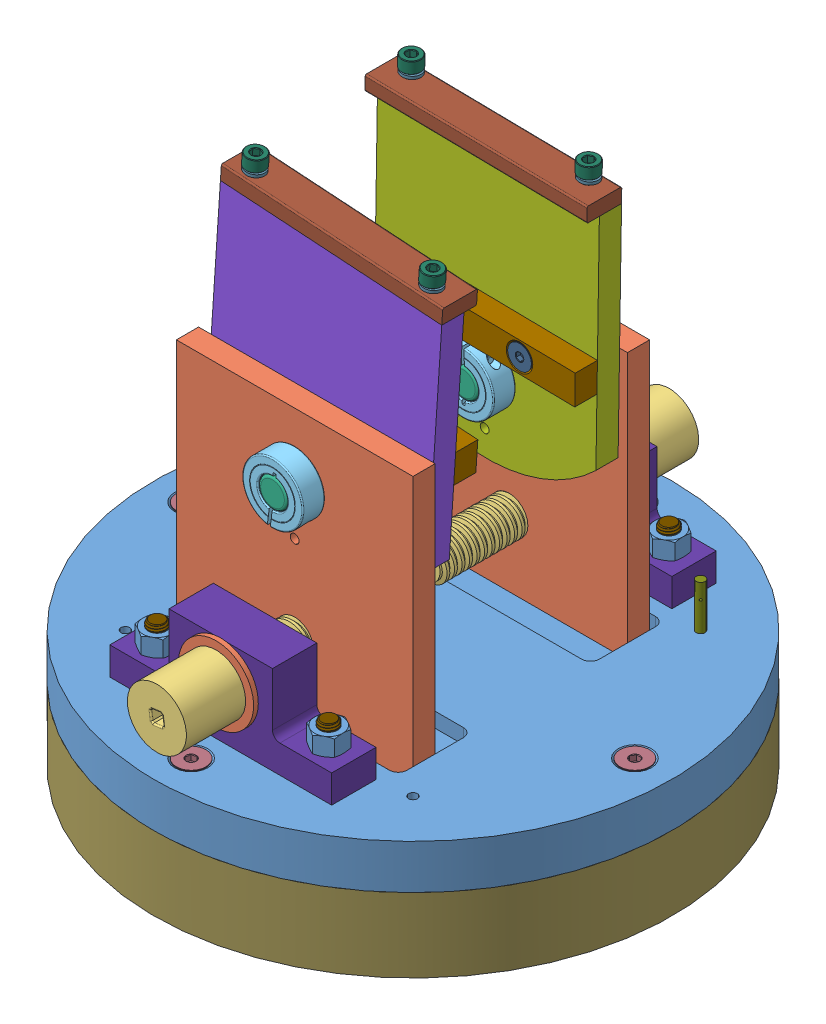
SolidWorks assembly Satalite mount assembly, configuration Default. Lengths in mm.
Overall size (350 354.15 350).
53 component instances, 21 part files, 116 mates.
Components (placement in the parent):
- satalite mount bottom plate-1: satalite mount bottom plate [Default] at (141.1689 151.6595 277.362) size (350 30 350)
- Satalite mount outside plate-1: Satalite mount outside plate [Default] at (141.1689 266.6595 342.352) size (160 180 15)
- Satalite mount outside plate-2: Satalite mount outside plate [Default] at (141.1689 266.6595 197.372) size (160 180 15)
- 20mm shaft buffer-1: 20mm shaft buffer [Default] at (141.1689 309.1595 342.352) x (1 0 0) z (0 1 0) size (25 1 25)
- rotory shaft outer plastic bearing-1: rotory shaft outer plastic bearing [Default] at (141.1689 309.1595 342.352) size (26 26 15)
- rotory shaft outer plastic bearing-2: rotory shaft outer plastic bearing [Default] at (141.1689 309.1595 342.352) x (0.815735 -0.578426 0) z (0 0 1) size (26 26 15)
- rotory shaft outer plastic bearing-3: rotory shaft outer plastic bearing [Default] at (141.1689 309.1595 197.372) size (26 26 15)
- rotory shaft outer plastic bearing-4: rotory shaft outer plastic bearing [Default] at (141.1689 309.1595 197.372) size (26 26 15)
- 20mm shaft collar-1: 20mm shaft collar [57445K73] at (141.1689 309.1595 318.852) x (-0.923728 -0.383049 0) z (0 0 -1) size (41 41.02 15.09)
- 20mm shaft collar-2: 20mm shaft collar [57445K73] at (141.1689 309.1595 364.852) x (-0.992379 0.123223 0) z (0 0 1) size (41 41.02 15.09)
- 20mm shaft collar-3: 20mm shaft collar [57445K73] at (141.1689 309.1595 235.872) x (0.999679 0.025332 0) z (0 0 1) size (41 41.02 15.09)
- 20mm shaft collar-4: 20mm shaft collar [57445K73] at (141.1689 309.1595 189.872) x (0.923728 0.383049 0) z (0 0 -1) size (41 41.02 15.09)
- 20mm shaft-1: 20mm shaft [Default] at (141.1689 309.1595 182.372) x (0.421421 -0.906865 0) z (-0.906865 -0.421421 0) size (20 61 20)
- 20mm shaft-2: 20mm shaft [Default] at (141.1689 309.1595 311.352) x (0.923728 0.383049 0) z (0.383049 -0.923728 0) size (20 61 20)
- 20mm shaft buffer-2: 20mm shaft buffer [Default] at (141.1689 309.1595 212.372) x (1 0 0) z (0 -1 0) size (25 1 25)
- satalite rightside inside mount-4: satalite rightside inside mount [Default] at (142.4964 394.1491 213.372) x (0.999878 -0.015617 0) z (0 0 1) size (150 181.07 15)
- satalite left mount-2: satalite left mount [Default] at (146.7984 393.9729 326.352) x (0.997804 -0.066229 0) z (0 0 1) size (150 181.07 15)
- satalite mount side rest-1: satalite mount side rest [Default] at (141.7155 344.1552 243.372) x (-0.999878 0.015617 0) z (0 0 -1) size (150 20 15)
- M8 22mm ctrsk screw-1: M8 22mm ctrsk screw [91294A285] at (104.2201 344.7409 243.372) size (16 16 22.74)
- M8 22mm ctrsk screw-2: M8 22mm ctrsk screw [91294A285] at (179.211 343.5696 243.372) size (16 16 22.74)
- satalite mount side rest-2: satalite mount side rest [Default] at (143.487 344.0827 311.352) x (0.997804 -0.066229 0) z (0 0 1) size (150 20 15)
- M8 22mm ctrsk screw-3: M8 22mm ctrsk screw [91294A285] at (180.9046 341.5991 311.352) x (0.640146 0.768253 0) z (0 0 -1) size (16 16 22.74)
- M8 22mm ctrsk screw-4: M8 22mm ctrsk screw [91294A285] at (106.0693 346.5663 310.952) x (-0.483512 -0.875338 0) z (0 0 -1) size (16 16 22.74)
- satalite mount adjustable clamp-1: satalite mount adjustable clamp [Default] at (68.2864 445.3144 225.122) x (0 0 -1) z (-0.015617 -0.999878 0) size (23.5 150 10)
- satalite mount adjustable clamp-2: satalite mount adjustable clamp [Default] at (224.9452 438.8959 329.602) x (0 0 1) z (-0.066229 -0.997804 0) size (23.5 150 10)
- Rotary table top plate-1: Rotary table top plate [Default] at (141.1689 121.6595 277.362) x (0.707107 0 0.707107) z (-0.707107 0 0.707107) size (350 50 350) (hidden)
- M10 hex 35mm-1: M10 hex 35mm [91304A165] at (141.1689 181.6595 427.362) x (-0.306479 0 -0.951877) z (0 1 0) size (20 20 35.94)
- M10 hex 35mm-2: M10 hex 35mm [91304A165] at (291.1689 181.6595 277.362) x (-0.884177 0 -0.467152) z (0 1 0) size (20 20 35.94)
- M10 hex 35mm-3: M10 hex 35mm [91304A165] at (-8.8311 181.6595 277.362) x (1 0 0) z (0 1 0) size (20 20 35.94)
- M10 hex 35mm-4: M10 hex 35mm [91304A165] at (141.1689 181.6595 127.362) x (1 0 0) z (0 1 0) size (20 20 35.94)
- M8 spring washer-1: M8 spring washer [91190A550] at (90.7238 455.1009 333.852) x (0.995294 -0.066063 -0.070888) z (0.070732 -0.004695 0.997484) size (12.81 4.18 14.61)
- M8 spring washer-2: M8 spring washer [91190A550] at (83.3983 452.3592 220.872) x (0.999878 -0.015617 0.000121) z (-0.00012 0.000002 1) size (12.81 4.18 14.61)
- M8 spring washer-3: M8 spring washer [91190A550] at (210.4603 447.1534 333.852) x (0.995294 -0.066063 -0.070888) z (0.070732 -0.004695 0.997484) size (12.81 4.18 14.61)
- M8 spring washer-4: M8 spring washer [91190A550] at (203.3837 450.4851 220.872) x (0.999878 -0.015617 0) z (0 0 1) size (12.81 4.18 14.61)
- M8 Hex fastener 45mm L-1: M8 Hex fastener 45mm L [91290A446] at (87.8693 412.0955 333.852) x (0.986596 -0.065486 -0.149465) z (-0.066229 -0.997804 0) size (13 13 53.81)
- M8 Hex fastener 45mm L-2: M8 Hex fastener 45mm L [91290A446] at (82.7252 409.2645 220.872) x (0.997959 -0.015587 0.061925) z (-0.015617 -0.999878 0) size (13 13 53.81)
- M8 Hex fastener 45mm L-3: M8 Hex fastener 45mm L [91290A446] at (207.6058 404.148 333.852) x (0.986596 -0.065486 -0.149465) z (-0.066229 -0.997804 0) size (13 13 53.81)
- M8 Hex fastener 45mm L-4: M8 Hex fastener 45mm L [91290A446] at (202.7106 407.3904 220.872) x (0.997959 -0.015587 0.061925) z (-0.015617 -0.999878 0) size (13 13 53.81)
- quick release pin-1: quick release pin [Default] at (238.3961 111.6595 180.1348) size (5.98 100 15.53)
- mount vice mount-1: mount vice mount [Default] at (141.1689 205.1118 147.362) size (150 60 30)
- mount vice mount-2: mount vice mount [Default] at (141.1689 205.1118 377.362) size (150 60 30)
- M12_65L_hex-1: M12_65L_hex [91294A556] at (83.1689 151.6595 392.362) x (1 0 0) z (0 -1 0) size (24 24 66.3)
- M12_65L_hex-2: M12_65L_hex [91294A556] at (199.1689 151.6595 392.362) x (1 0 0) z (0 -1 0) size (24 24 66.3)
- M12_65L_hex-3: M12_65L_hex [91294A556] at (199.1689 151.6595 162.362) x (1 0 0) z (0 -1 0) size (24 24 66.3)
- M12_65L_hex-4: M12_65L_hex [91294A556] at (83.1689 151.6595 162.362) x (1 0 0) z (0 -1 0) size (24 24 66.3)
- M12 Nut-1: M12 Nut [90725A725] at (199.1689 206.5419 162.362) size (19 13.08 21.94)
- M12 Nut-2: M12 Nut [90725A725] at (83.1689 206.5419 162.362) size (19 13.08 21.94)
- M12 Nut-3: M12 Nut [90725A725] at (199.1689 206.5419 392.362) size (19 13.08 21.94)
- M12 Nut-4: M12 Nut [90725A725] at (83.1689 206.5419 392.362) size (19 13.08 21.94)
- Vise bushing-1: Vise bushing [Default] at (141.1689 216.6595 410.537) x (1 0 0) z (0 1 0) size (50.8 3.17 50.8)
- Vise_shaft-1: Vise_shaft [Default] at (141.1689 216.6595 410.537) x (0.991544 0.129771 0) z (-0.129771 0.991544 0) size (40 165 40)
- Vise_shaft-2: Vise_shaft [Default] at (141.1689 216.6595 144.187) x (1 0 0) z (0 -1 0) size (40 165 40)
- Vise bushing-2: Vise bushing [Default] at (141.1689 216.6595 144.187) x (1 0 0) z (0 -1 0) size (50.8 3.17 50.8)
Mates (geometry in assembly coordinates):
- Coincident3: coincident aligned: plane of Satalite mount outside plate-1 through (141.1689 266.6595 357.352) normal (0 0 1); plane of rotory shaft outer plastic bearing-1 through (141.1689 309.1595 357.352) normal (0 0 1)
- Concentric2: concentric anti-aligned: cylinder of Satalite mount outside plate-1 through (141.1689 309.1595 357.352) axis (0 0 1) radius 13.005; cylinder of rotory shaft outer plastic bearing-1 through (141.1689 309.1595 357.352) axis (0 0 -1) radius 10
- Concentric5: concentric anti-aligned: cylinder of Satalite mount outside plate-2 through (141.1689 309.1595 212.372) axis (0 0 1) radius 13.005; cylinder of rotory shaft outer plastic bearing-3 through (141.1689 309.1595 212.372) axis (0 0 -1) radius 10
- Concentric6: concentric anti-aligned: cylinder of Satalite mount outside plate-2 through (141.1689 309.1595 212.372) axis (0 0 1) radius 13.005; cylinder of rotory shaft outer plastic bearing-3 through (141.1689 309.1595 212.372) axis (0 0 -1) radius 10
- Coincident6: coincident aligned: plane of Satalite mount outside plate-2 through (141.1689 266.6595 212.372) normal (0 0 1); plane of rotory shaft outer plastic bearing-3 through (141.1689 309.1595 212.372) normal (0 0 1)
- Concentric7: concentric anti-aligned: cylinder of 20mm shaft buffer-1 through (141.1689 309.1595 341.352) axis (0 0 1) radius 10.05; cylinder of rotory shaft outer plastic bearing-2 through (141.1689 309.1595 357.352) axis (0 0 -1) radius 10
- Coincident8: coincident anti-aligned: plane of Satalite mount outside plate-1 through (141.1689 266.6595 342.352) normal (0 0 -1); plane of 20mm shaft buffer-1 through (141.1689 309.1595 342.352) normal (0 0 1)
- Coincident10: coincident anti-aligned: plane of Satalite mount outside plate-1 through (141.1689 266.6595 357.352) normal (0 0 1); plane of 20mm shaft collar-2 through (141.1689 309.1595 357.352) normal (0 0 -1)
- Concentric8: concentric aligned: cylinder of rotory shaft outer plastic bearing-1 through (141.1689 309.1595 357.352) axis (0 0 -1) radius 10; cylinder of 20mm shaft collar-2 through (141.1689 309.1595 372.352) axis (0 0 -1) radius 10
- Coincident11: coincident aligned: plane of 20mm shaft collar-2 through (141.1689 309.1595 372.352) normal (0 0 1); plane of 20mm shaft-2 through (141.1689 309.1595 372.352) normal (0 0 1)
- Concentric9: concentric aligned: cylinder of 20mm shaft collar-2 through (141.1689 309.1595 372.352) axis (0 0 -1) radius 10; cylinder of 20mm shaft-2 through (141.1689 309.1595 372.352) axis (0 0 -1) radius 10
- Concentric10: concentric anti-aligned: cylinder of 20mm shaft collar-1 through (141.1689 309.1595 311.352) axis (0 0 1) radius 10; cylinder of 20mm shaft-2 through (141.1689 309.1595 372.352) axis (0 0 -1) radius 10
- Concentric11: concentric aligned: cylinder of rotory shaft outer plastic bearing-4 through (141.1689 309.1595 212.372) axis (0 0 -1) radius 10; cylinder of 20mm shaft buffer-2 through (141.1689 309.1595 213.372) axis (0 0 -1) radius 10.05
- Coincident16: coincident anti-aligned: plane of Satalite mount outside plate-2 through (141.1689 266.6595 212.372) normal (0 0 1); plane of 20mm shaft buffer-2 through (141.1689 309.1595 212.372) normal (0 0 -1)
- Concentric12: concentric aligned: cylinder of rotory shaft outer plastic bearing-3 through (141.1689 309.1595 212.372) axis (0 0 -1) radius 10; cylinder of rotory shaft outer plastic bearing-4 through (141.1689 309.1595 212.372) axis (0 0 -1) radius 10
- Coincident18: coincident anti-aligned: plane of Satalite mount outside plate-2 through (141.1689 266.6595 197.372) normal (0 0 -1); plane of 20mm shaft collar-4 through (141.1689 309.1595 197.372) normal (0 0 1)
- Coincident19: coincident aligned: plane of 20mm shaft collar-4 through (141.1689 309.1595 182.372) normal (0 0 -1); plane of 20mm shaft-1 through (141.1689 309.1595 182.372) normal (0 0 -1)
- Concentric15: concentric anti-aligned: cylinder of 20mm shaft collar-4 through (141.1689 309.1595 182.372) axis (0 0 1) radius 10; cylinder of 20mm shaft-1 through (141.1689 309.1595 243.372) axis (0 0 -1) radius 10
- Concentric16: concentric aligned: cylinder of 20mm shaft collar-3 through (141.1689 309.1595 243.372) axis (0 0 -1) radius 10; cylinder of 20mm shaft-1 through (141.1689 309.1595 243.372) axis (0 0 -1) radius 10
- Concentric17: concentric anti-aligned: cylinder of rotory shaft outer plastic bearing-2 through (141.1689 309.1595 357.352) axis (0 0 -1) radius 13; cylinder of satalite left mount-2 through (141.1689 309.1595 326.352) axis (0 0 1) radius 13.005
- Coincident21: coincident anti-aligned: circle of 20mm shaft collar-1; plane of satalite left mount-2 through (146.7984 393.9729 326.352) normal (0 0 -1)
- Coincident22: coincident aligned: plane of 20mm shaft collar-1 through (141.1689 309.1595 311.352) normal (0 0 -1); plane of 20mm shaft-2 through (141.1689 309.1595 311.352) normal (0 0 -1)
- Concentric18: concentric aligned: cylinder of rotory shaft outer plastic bearing-2 through (141.1689 309.1595 357.352) axis (0 0 -1) radius 10; cylinder of 20mm shaft-2 through (141.1689 309.1595 372.352) axis (0 0 -1) radius 10
- Concentric19: concentric aligned: circle of 20mm shaft-1; cylinder of satalite rightside inside mount-4 through (141.1689 309.1595 213.372) axis (0 0 1) radius 13.005
- Coincident24: coincident anti-aligned: plane of 20mm shaft collar-3 through (141.1689 309.1595 228.372) normal (0 0 -1); plane of satalite rightside inside mount-4 through (142.4964 394.1491 228.372) normal (0 0 1)
- Concentric20: concentric aligned: cylinder of rotory shaft outer plastic bearing-4 through (141.1689 309.1595 212.372) axis (0 0 -1) radius 10; cylinder of 20mm shaft-1 through (141.1689 309.1595 243.372) axis (0 0 -1) radius 10
- Coincident25: coincident aligned: plane of 20mm shaft collar-3 through (141.1689 309.1595 243.372) normal (0 0 1); plane of 20mm shaft-1 through (141.1689 309.1595 243.372) normal (0 0 1)
- Coincident26: coincident anti-aligned: plane of satalite rightside inside mount-4 through (142.4964 394.1491 228.372) normal (0 0 1); plane of satalite mount side rest-1 through (141.7155 344.1552 228.372) normal (0 0 -1)
- Parallel2: parallel aligned: plane of satalite rightside inside mount-4 through (217.4873 392.9778 228.372) normal (0.999878 -0.015617 0); plane of satalite mount side rest-1 through (216.5502 332.9852 228.372) normal (0.999878 -0.015617 0)
- Concentric21: concentric aligned: cylinder of satalite rightside inside mount-4 through (179.211 343.5696 228.372) axis (0 0 1) radius 3.4; cylinder of satalite mount side rest-1 through (179.211 343.5696 243.372) axis (0 0 1) radius 4.5
- Coincident29: coincident aligned: plane of satalite mount side rest-1 through (141.7155 344.1552 243.372) normal (0 0 1); plane of M8 22mm ctrsk screw-1 through (104.2201 340.7409 243.372) normal (0 0 1)
- Concentric22: concentric aligned: cylinder of satalite mount side rest-1 through (104.2201 344.7409 243.372) axis (0 0 1) radius 4.5; circle of M8 22mm ctrsk screw-1
- Coincident30: coincident aligned: plane of satalite mount side rest-1 through (141.7155 344.1552 243.372) normal (0 0 1); plane of M8 22mm ctrsk screw-2 through (179.211 339.5696 243.372) normal (0 0 1)
- Concentric23: concentric aligned: cylinder of satalite mount side rest-1 through (179.211 343.5696 243.372) axis (0 0 1) radius 4.5; circle of M8 22mm ctrsk screw-2
- Coincident31: coincident anti-aligned: plane of satalite left mount-2 through (146.7984 393.9729 326.352) normal (0 0 -1); plane of satalite mount side rest-2 through (143.487 344.0827 326.352) normal (0 0 1)
- Parallel3: parallel aligned: plane of satalite left mount-2 through (221.6338 389.0057 341.352) normal (0.997804 -0.066229 0); plane of satalite mount side rest-2 through (217.66 329.1374 326.352) normal (0.997804 -0.066229 0)
- Concentric24: concentric aligned: cylinder of satalite left mount-2 through (180.9046 341.5991 326.352) axis (0 0 -1) radius 3.4; cylinder of satalite mount side rest-2 through (180.9046 341.5991 311.352) axis (0 0 -1) radius 4.5
- Concentric25: concentric aligned: cylinder of satalite mount side rest-2 through (180.9046 341.5991 311.352) axis (0 0 -1) radius 4.5; cylinder of M8 22mm ctrsk screw-3 through (180.9046 341.5991 311.352) axis (0 0 -1) radius 8
- Coincident33: coincident aligned: plane of satalite mount side rest-2 through (143.487 344.0827 311.352) normal (0 0 -1); plane of M8 22mm ctrsk screw-3 through (177.8316 344.1596 311.352) normal (0 0 -1)
- Coincident34: coincident aligned: plane of satalite mount side rest-2 through (143.487 344.0827 311.352) normal (0 0 -1); circle of M8 22mm ctrsk screw-4
- Concentric26: concentric aligned: cylinder of satalite mount side rest-2 through (106.0693 346.5663 311.352) axis (0 0 -1) radius 4.5; cylinder of M8 22mm ctrsk screw-4 through (106.0693 346.5663 310.952) axis (0 0 -1) radius 8
- Coincident35: coincident anti-aligned: plane of satalite left mount-2 through (149.7788 438.8741 341.352) normal (0.066229 0.997804 0); plane of satalite mount adjustable clamp-2 through (74.9434 443.8413 318.852) normal (-0.066229 -0.997804 0)
- Concentric27: concentric aligned: cylinder of satalite left mount-2 through (89.9105 442.8479 333.852) axis (0.066229 0.997804 0) radius 3.4; cylinder of satalite mount adjustable clamp-2 through (90.5728 452.8259 333.852) axis (0.066229 0.997804 0) radius 4.5
- Concentric28: concentric aligned: cylinder of satalite left mount-2 through (209.647 434.9003 333.852) axis (0.066229 0.997804 0) radius 3.4; cylinder of satalite mount adjustable clamp-2 through (210.3093 444.8784 333.852) axis (0.066229 0.997804 0) radius 4.5
- Coincident38: coincident anti-aligned: plane of satalite rightside inside mount-4 through (143.1992 439.1437 228.372) normal (0.015617 0.999878 0); plane of satalite mount adjustable clamp-1 through (218.1901 437.9724 235.872) normal (-0.015617 -0.999878 0)
- Concentric29: concentric aligned: cylinder of satalite rightside inside mount-4 through (203.1919 438.2066 220.872) axis (0.015617 0.999878 0) radius 3.4; cylinder of satalite mount adjustable clamp-1 through (203.3481 448.2054 220.872) axis (0.015617 0.999878 0) radius 4.5
- Concentric30: concentric aligned: cylinder of satalite rightside inside mount-4 through (83.2065 440.0807 220.872) axis (0.015617 0.999878 0) radius 3.4; cylinder of satalite mount adjustable clamp-1 through (83.3627 450.0795 220.872) axis (0.015617 0.999878 0) radius 4.5
- Concentric34: concentric aligned: cylinder of satalite mount bottom plate-1 through (141.1689 181.6595 277.362) axis (0 -1 0) radius 175; cylinder of Rotary table top plate-1 through (141.1689 151.6595 277.362) axis (0 -1 0) radius 175
- Parallel6: parallel aligned: line of satalite mount bottom plate-1 through (141.1689 181.6595 277.362) axis (-1 0 0); line of Rotary table top plate-1 through (291.1689 151.6595 277.362) axis (-1 0 0)
- Coincident45: coincident aligned: circle of satalite mount bottom plate-1; plane of Rotary table top plate-1 through (141.1689 151.6595 277.362) normal (0 1 0)
- Concentric35: concentric aligned: circle of satalite mount bottom plate-1; circle of M10 hex 35mm-1
- Coincident46: coincident aligned: plane of satalite mount bottom plate-1 through (141.1689 181.6595 277.362) normal (0 1 0); plane of M10 hex 35mm-1 through (145.9283 181.6595 425.8296) normal (0 1 0)
- Concentric36: concentric aligned: circle of satalite mount bottom plate-1; circle of M10 hex 35mm-2
- Coincident47: coincident aligned: plane of satalite mount bottom plate-1 through (141.1689 181.6595 277.362) normal (0 1 0); plane of M10 hex 35mm-2 through (293.5047 181.6595 272.9411) normal (0 1 0)
- Coincident48: coincident aligned: plane of satalite mount bottom plate-1 through (141.1689 181.6595 277.362) normal (0 1 0); plane of M10 hex 35mm-4 through (141.1689 181.6595 132.362) normal (0 1 0)
- Concentric37: concentric aligned: circle of satalite mount bottom plate-1; circle of M10 hex 35mm-4
- Coincident49: coincident aligned: plane of satalite mount bottom plate-1 through (141.1689 181.6595 277.362) normal (0 1 0); plane of M10 hex 35mm-3 through (-8.8311 181.6595 282.362) normal (0 1 0)
- Concentric38: concentric aligned: circle of satalite mount bottom plate-1; circle of M10 hex 35mm-3
- Concentric39: concentric anti-aligned: circle of satalite mount adjustable clamp-2; cylinder of M8 spring washer-1 through (90.7238 455.1009 333.852) axis (-0.066229 -0.997804 0) radius 4.25
- Coincident50: coincident: plane of satalite mount adjustable clamp-2 through (75.6057 453.8193 318.852) normal (0.066229 0.997804 0); line of M8 spring washer-1 through (84.2369 453.2464 333.9035) axis (0.997772 -0.066227 -0.008115)
- Concentric40: concentric anti-aligned: cylinder of satalite mount adjustable clamp-2 through (210.3093 444.8784 333.852) axis (0.066229 0.997804 0) radius 4.5; cylinder of M8 spring washer-3 through (210.4603 447.1534 333.852) axis (-0.066229 -0.997804 0) radius 4.25
- Coincident51: coincident: plane of satalite mount adjustable clamp-2 through (75.6057 453.8193 318.852) normal (0.066229 0.997804 0); line of M8 spring washer-3 through (203.9735 445.2989 333.9035) axis (0.997772 -0.066227 -0.008115)
- Coincident52: coincident: plane of satalite mount adjustable clamp-1 through (218.3462 447.9711 235.872) normal (0.015617 0.999878 0); line of M8 spring washer-2 through (77.026 450.1785 220.4725) axis (0.997897 -0.015586 0.062911)
- Concentric41: concentric anti-aligned: cylinder of satalite mount adjustable clamp-1 through (83.3627 450.0795 220.872) axis (0.015617 0.999878 0) radius 4.5; cylinder of M8 spring washer-2 through (83.3983 452.3592 220.872) axis (-0.015617 -0.999878 0) radius 4.25
- Concentric42: concentric anti-aligned: cylinder of satalite mount adjustable clamp-1 through (203.3481 448.2054 220.872) axis (0.015617 0.999878 0) radius 4.5; cylinder of M8 spring washer-4 through (203.3837 450.4851 220.872) axis (-0.015617 -0.999878 0) radius 4.25
- Coincident53: coincident: plane of satalite mount adjustable clamp-1 through (218.3462 447.9711 235.872) normal (0.015617 0.999878 0); line of M8 spring washer-4 through (197.0114 448.3044 220.4733) axis (0.997905 -0.015587 0.062791)
- Concentric43: concentric aligned: cylinder of M8 spring washer-2 through (83.3983 452.3592 220.872) axis (-0.015617 -0.999878 0) radius 4.25; cylinder of M8 Hex fastener 45mm L-2 through (83.428 454.259 220.872) axis (-0.015617 -0.999878 0) radius 4
- Coincident54: coincident: line of M8 spring washer-2 through (77.0787 454.3581 220.8712) axis (0.999878 -0.015617 0.000121); plane of M8 Hex fastener 45mm L-2 through (83.428 454.259 220.872) normal (-0.015617 -0.999878 0)
- Concentric44: concentric aligned: cylinder of M8 spring washer-4 through (203.3837 450.4851 220.872) axis (-0.015617 -0.999878 0) radius 4.25; cylinder of M8 Hex fastener 45mm L-4 through (203.4133 452.3849 220.872) axis (-0.015617 -0.999878 0) radius 4
- Coincident55: coincident: line of M8 spring washer-4 through (197.0641 452.4841 220.872) axis (0.999878 -0.015617 0); plane of M8 Hex fastener 45mm L-4 through (203.4133 452.3849 220.872) normal (-0.015617 -0.999878 0)
- Concentric45: concentric aligned: cylinder of M8 spring washer-1 through (90.7238 455.1009 333.852) axis (-0.066229 -0.997804 0) radius 4.25; cylinder of M8 Hex fastener 45mm L-1 through (90.8496 456.9967 333.852) axis (-0.066229 -0.997804 0) radius 4
- Coincident57: coincident: line of M8 spring washer-1 through (86.6196 457.2775 334.1533) axis (-0.995294 0.066063 0.070888); plane of M8 Hex fastener 45mm L-1 through (90.8496 456.9967 333.852) normal (-0.066229 -0.997804 0)
- Concentric46: concentric anti-aligned: cylinder of satalite mount adjustable clamp-2 through (210.3093 444.8784 333.852) axis (0.066229 0.997804 0) radius 4.5; cylinder of M8 Hex fastener 45mm L-3 through (210.5862 449.0492 333.852) axis (-0.066229 -0.997804 0) radius 4
- Coincident58: coincident: line of M8 spring washer-3 through (204.266 449.4687 334.3021) axis (0.995294 -0.066063 -0.070888); plane of M8 Hex fastener 45mm L-3 through (210.5862 449.0492 333.852) normal (-0.066229 -0.997804 0)
- Distance1: distance = 30 mm aligned: plane of quick release pin-1 through (238.3961 211.6595 180.1348) normal (0 1 0); plane of satalite mount bottom plate-1 through (141.1689 181.6595 277.362) normal (0 1 0)
- Concentric47: concentric anti-aligned: cylinder of satalite mount bottom plate-1 through (238.3961 181.6595 180.1348) axis (0 1 0) radius 3; cylinder of quick release pin-1 through (238.3961 211.6595 180.1348) axis (0 -1 0) radius 2.99
- Coincident59: coincident anti-aligned: plane of satalite mount bottom plate-1 through (221.1689 171.6595 323.362) normal (-1 0 0); plane of Satalite mount outside plate-1 through (221.1689 171.6595 357.352) normal (1 0 0)
- Coincident60: coincident: plane of satalite mount bottom plate-1 through (215.1689 171.6595 361.362) normal (0 1 0); line of Satalite mount outside plate-1 through (61.1689 171.6595 357.352) axis (1 0 0)
- Coincident62: coincident aligned: plane of Satalite mount outside plate-1 through (141.1689 266.6595 357.352) normal (0 0 1); plane of rotory shaft outer plastic bearing-2 through (141.1689 309.1595 357.352) normal (0 0 1)
- Coincident65: coincident: line of satalite mount bottom plate-1 through (61.1689 181.6595 342.352) axis (1 0 0); plane of Satalite mount outside plate-1 through (141.1689 266.6595 342.352) normal (0 0 -1)
- Coincident66: coincident aligned: plane of Satalite mount outside plate-2 through (141.1689 266.6595 197.372) normal (0 0 -1); plane of rotory shaft outer plastic bearing-4 through (141.1689 309.1595 197.372) normal (0 0 -1)
- Coincident68: coincident: line of satalite mount bottom plate-1 through (61.1689 181.6595 212.372) axis (1 0 0); plane of Satalite mount outside plate-2 through (141.1689 266.6595 212.372) normal (0 0 1)
- Coincident69: coincident anti-aligned: plane of satalite mount bottom plate-1 through (141.1689 181.6595 277.362) normal (0 1 0); plane of mount vice mount-1 through (66.1689 181.6595 177.362) normal (0 -1 0)
- Coincident70: coincident anti-aligned: plane of satalite mount bottom plate-1 through (141.1689 181.6595 277.362) normal (0 1 0); plane of mount vice mount-2 through (66.1689 181.6595 407.362) normal (0 -1 0)
- Parallel8: parallel aligned: line of satalite mount bottom plate-1 through (-33.8311 181.6595 277.362) axis (1 0 0); line of mount vice mount-2 through (66.1689 181.6595 377.362) axis (1 0 0)
- Parallel9: parallel aligned: line of satalite mount bottom plate-1 through (-33.8311 181.6595 277.362) axis (1 0 0); line of mount vice mount-1 through (66.1689 181.6595 147.362) axis (1 0 0)
- Coincident73: coincident: line of satalite mount bottom plate-1 through (141.1689 181.6595 277.362) axis (0 0 -1); moEndPointRef_w of mount vice mount-1
- Coincident74: coincident: line of satalite mount bottom plate-1 through (141.1689 181.6595 277.362) axis (0 0 1); moEndPointRef_w of mount vice mount-2
- Distance3: distance = 100 mm: line of satalite mount bottom plate-1 through (-33.8311 181.6595 277.362) axis (1 0 0); line of mount vice mount-2 through (66.1689 181.6595 377.362) axis (1 0 0)
- Distance4: distance = 100 mm: line of satalite mount bottom plate-1 through (-33.8311 181.6595 277.362) axis (1 0 0); line of mount vice mount-1 through (66.1689 181.6595 177.362) axis (1 0 0)
- Coincident77: coincident aligned: plane of satalite mount bottom plate-1 through (141.1689 151.6595 277.362) normal (0 -1 0); plane of M12_65L_hex-3 through (199.1689 151.6595 156.362) normal (0 -1 0)
- Coincident78: coincident aligned: plane of satalite mount bottom plate-1 through (141.1689 151.6595 277.362) normal (0 -1 0); plane of M12_65L_hex-4 through (83.1689 151.6595 156.362) normal (0 -1 0)
- Coincident79: coincident aligned: plane of satalite mount bottom plate-1 through (141.1689 151.6595 277.362) normal (0 -1 0); plane of M12_65L_hex-1 through (83.1689 151.6595 386.362) normal (0 -1 0)
- Coincident80: coincident aligned: plane of satalite mount bottom plate-1 through (141.1689 151.6595 277.362) normal (0 -1 0); plane of M12_65L_hex-2 through (199.1689 151.6595 386.362) normal (0 -1 0)
- Concentric48: concentric anti-aligned: circle of satalite mount bottom plate-1; circle of M12_65L_hex-3
- Concentric49: concentric anti-aligned: circle of satalite mount bottom plate-1; circle of M12_65L_hex-4
- Concentric50: concentric anti-aligned: circle of satalite mount bottom plate-1; circle of M12_65L_hex-1
- Concentric51: concentric anti-aligned: circle of satalite mount bottom plate-1; circle of M12_65L_hex-2
- Coincident82: coincident anti-aligned: plane of mount vice mount-1 through (216.1689 200.5419 177.362) normal (0 1 0); plane of M12 Nut-1 through (189.6689 200.5419 145.9075) normal (0 -1 0)
- Concentric52: concentric anti-aligned: circle of M12_65L_hex-3; circle of M12 Nut-1
- Coincident83: coincident anti-aligned: plane of mount vice mount-1 through (66.1689 200.5419 177.362) normal (0 1 0); plane of M12 Nut-2 through (73.6689 200.5419 145.9075) normal (0 -1 0)
- Concentric53: concentric anti-aligned: circle of M12_65L_hex-4; circle of M12 Nut-2
- Concentric54: concentric anti-aligned: circle of M12_65L_hex-2; circle of M12 Nut-3
- Coincident84: coincident anti-aligned: plane of mount vice mount-2 through (216.1689 200.5419 407.362) normal (0 1 0); plane of M12 Nut-3 through (189.6689 200.5419 375.9075) normal (0 -1 0)
- Concentric55: concentric anti-aligned: circle of M12_65L_hex-1; circle of M12 Nut-4
- Coincident85: coincident anti-aligned: plane of mount vice mount-2 through (66.1689 200.5419 407.362) normal (0 1 0); plane of M12 Nut-4 through (73.6689 200.5419 375.9075) normal (0 -1 0)
- Coincident86: coincident anti-aligned: plane of mount vice mount-2 through (101.1689 205.5419 407.362) normal (0 0 1); plane of Vise bushing-1 through (141.1689 216.6595 407.362) normal (0 0 -1)
- Concentric56: concentric aligned: cylinder of Vise bushing-1 through (141.1689 216.6595 407.362) axis (0 0 1) radius 12.7; cylinder of mount vice mount-2 through (141.1689 216.6595 407.362) axis (0 0 1) radius 12.7
- Concentric59: concentric anti-aligned: circle of Vise bushing-1; circle of Vise_shaft-1
- Coincident89: coincident anti-aligned: plane of Vise bushing-1 through (141.1689 216.6595 410.537) normal (0 0 1); plane of Vise_shaft-1 through (141.1689 216.6595 410.537) normal (0 0 -1)
- Concentric60: concentric anti-aligned: circle of Satalite mount outside plate-2; circle of Vise_shaft-1
- Parallel10: parallel anti-aligned: line of satalite mount bottom plate-1 through (215.1689 171.6595 187.362) axis (-1 0 0); line of Satalite mount outside plate-2 through (61.1689 171.6595 197.372) axis (1 0 0)
- Coincident90: coincident anti-aligned: plane of mount vice mount-1 through (101.1689 205.5419 147.362) normal (0 0 -1); plane of Vise bushing-2 through (141.1689 216.6595 147.362) normal (0 0 1)
- Concentric61: concentric anti-aligned: cylinder of mount vice mount-1 through (141.1689 216.6595 177.362) axis (0 0 1) radius 12.7; cylinder of Vise bushing-2 through (141.1689 216.6595 147.362) axis (0 0 -1) radius 12.7
- Coincident91: coincident anti-aligned: plane of Vise_shaft-2 through (141.1689 216.6595 144.187) normal (0 0 1); plane of Vise bushing-2 through (141.1689 216.6595 144.187) normal (0 0 -1)
- Concentric62: concentric aligned: cylinder of mount vice mount-1 through (141.1689 216.6595 177.362) axis (0 0 1) radius 12.7; circle of Vise_shaft-2
